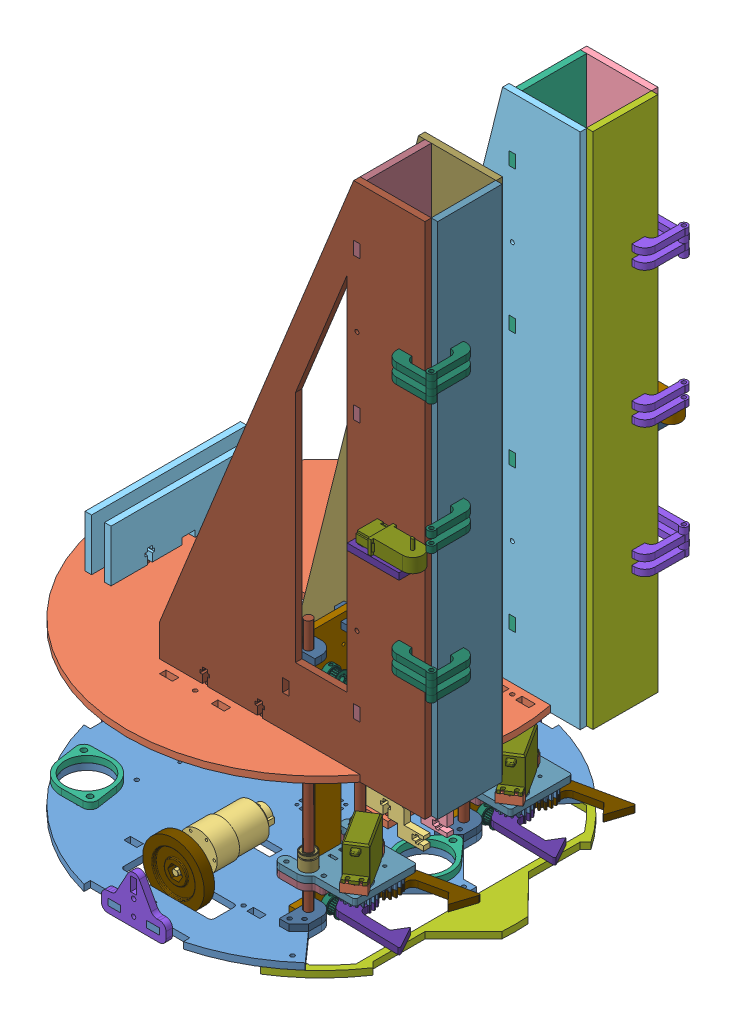
SolidWorks assembly Bot, configuration Default. Lengths in mm.
Overall size (426.1 677.49 381).
102 component instances, 45 part files, 65 mates.
Components (placement in the parent):
- Layer0-1: Layer0 [Default] at (287.9102 -30.6226 -253.9545) size (330.2 6.35 368.3)
- Layer1-1: Layer1 [Default] at (287.9102 128.1274 -253.9545) size (381 6.35 381)
- SideSupport-1: SideSupport [Default] at (364.1102 -24.2726 -133.3045) size (152.4 165.1 6.35) (hidden)
- SideSupport-2: SideSupport [Default] at (364.1102 -24.2726 -380.9545) size (152.4 165.1 6.35) (hidden)
- TailPlate-1: TailPlate [Default] at (138.6852 -30.6226 -291.5992) x (0 0 1) z (-1 0 0) size (76.2 165.1 6.35)
- BatteryHolder-1: BatteryHolder [Default] at (167.8952 -24.2726 -222.2045) x (0 0 -1) z (1 0 0) size (63.5 57.03 6.35)
- TabletHolder-1: TabletHolder [Default] at (138.6852 128.1274 -330.1545) x (0 0 1) z (-1 0 0) size (152.4 57.15 6.35)
- TabletHolder-2: TabletHolder [Default] at (157.7352 128.1274 -330.1545) x (0 0 1) z (-1 0 0) size (152.4 57.15 6.35)
- caster_spacer-1: caster_spacer [Default] at (152.6682 -24.2726 -348.652) x (0.584385 0 -0.811477) z (0 1 0) size (69.85 50.8 6.35)
- caster_spacer-2: caster_spacer [Default] at (152.6682 -17.9226 -159.257) x (0.760691 0 0.649114) z (0 -1 0) size (69.85 50.8 6.35)
- caster_spacer-3: caster_spacer [Default] at (389.5102 -17.9226 -253.9545) x (-0.01143 0 -0.999935) z (0 -1 0) size (69.85 50.8 6.35)
- CubeLimit-1: CubeLimit [Default] at (287.9102 -36.9726 -253.9545) size (88.9 6.35 322.29)
- ultra_short_ir_mount_plate-2: ultra_short_ir_mount_plate [Default] at (287.9102 -27.4476 -76.1545) size (63.5 47.06 6.35)
- ultra_short_ir_mount_plate-3: ultra_short_ir_mount_plate [Default] at (287.9102 -27.4476 -438.1045) size (63.5 47.06 6.35)
- ultra_short_ir_mount_plate-4: ultra_short_ir_mount_plate [Default] at (103.7602 -27.4476 -253.9545) x (0 0 -1) z (1 0 0) size (63.5 47.06 6.35)
- PulleyModule-1: PulleyModule [Default] at (324.3365 -56.1145 -530.8166) size (125.26 266.7 96.11)
  - PulleyBoard-1: PulleyBoard [Default] at (39.7737 6.4419 232.4121) size (6.35 247.65 63.5)
  - FrontBottom-1: FrontBottom [Default] at (39.7737 31.8419 340.3621) size (19.05 6.35 34.92)
  - FrontBottom-2: FrontBottom [Default] at (39.7737 38.1919 60.9621) x (1 0 0) z (0 0 -1) size (19.05 6.35 34.92)
  - Shaft8mm-1: Shaft8mm [Default] at (52.4737 31.8419 226.0621) size (8 254 8)
  - Shaft8mm-2: Shaft8mm [Default] at (52.4737 31.8419 175.2621) x (0.997108 0 -0.075996) z (0.075996 0 0.997108) size (8 254 8)
  - LM8UU-1: LM8UU [Default] at (52.4737 76.678 175.2621) x (0 -1 0) z (-0.618662 0 0.785658) size (24 15 15)
  - LM8UU-2: LM8UU [Default] at (52.4737 76.678 226.0621) x (0 -1 0) z (0 0 1) size (24 15 15)
  - 3DPrint-1: 3DPrint [Default] at (52.4737 61.503 200.6621) x (0 0 -1) z (1 0 0) size (73.42 6.35 41.67)
  - ClampSupport-1: ClampSupport [Default] at (52.4737 67.853 200.6621) x (0 0 -1) z (1 0 0) size (73.42 6.35 73.42)
  - GT2_20tooth-1: GT2_20tooth [Конфигурация1] at (46.1237 224.2919 200.6621) size (14 15 15)
  - GT2_20tooth-2: GT2_20tooth [Конфигурация1] at (46.1237 28.6669 200.6621) size (14 15 15)
  - power_hd_6001hb_servo-1: power_hd_6001hb_servo [Default] at (83.5903 112.303 204.4284) x (-0.538774 0 -0.84245) z (-0.84245 0 0.538774) size (54.5 43.74 20.07)
  - GearL-1: GearL [Default] at (89.3037 55.153 213.3621) x (0.999717 0 0.023781) z (-0.023781 0 0.999717) size (78.19 6.35 36.83)
  - GearR-1: GearR [Default] at (89.3037 55.153 187.9621) x (0.977961 0 -0.208788) z (0.208788 0 0.977961) size (78.31 6.35 36.71)
  - Gear-1: Gear [Default] at (89.3037 61.503 213.3621) x (0.947561 0 -0.319576) z (0.319576 0 0.947561) size (27.7 6.35 27.94)
  - Gear-2: Gear [Default] at (89.3037 61.503 187.9621) x (0.999359 0 -0.035795) z (0.035795 0 0.999359) size (27.7 6.35 27.94)
  - 3DPart2-1: 3DPart2 [Default] at (106.4689 74.203 221.7031) x (-0.538774 0 -0.84245) z (0.84245 0 -0.538774) size (54.5 8.56 20)
  - FrontBottom-3: FrontBottom [Default] at (-61.8263 254.0919 162.5621) x (0 0 1) z (-1 0 0) size (19.05 6.35 34.92)
  - FrontBottom-4: FrontBottom [Default] at (-61.8263 260.4419 238.7621) x (0 0 -1) z (-1 0 0) size (19.05 6.35 34.92)
- pololu_37d_29_motor_encoder-2: pololu_37d_29_motor_encoder [Default] at (287.914 -3.4296 -374.6045) x (0.000538 1 0) z (0 0 1) size (36.8 36.8 87.42)
- pololu_37d_29_motor_encoder-3: pololu_37d_29_motor_encoder [Default] at (287.9713 -3.4298 -133.3045) x (0.008727 0.999962 0) z (0 0 -1) size (36.8 36.8 87.42)
- ContainerUp-1: ContainerUp [Default] at (752.6603 -95.2272 -302.1038) x (0 0 1) z (-1 0 0) size (101.6 508 280.05)
  - ContainerTop-1: ContainerTop [Default] at (-66.1507 223.3546 509.2001) size (6.35 508 260.35)
  - ContainerBottom-1: ContainerBottom [Default] at (3.6993 223.3546 445.7001) x (0 0 -1) z (1 0 0) size (196.85 508 6.35)
  - ContainerLeft-1: ContainerLeft [Default] at (-66.1507 223.3546 312.3501) size (76.2 501.65 6.35)
  - ContainerRight-1: ContainerRight [Default] at (-59.8461 223.3546 242.5754) x (-0.004755 0 0.999989) z (-0.999989 0 -0.004755) size (6.35 508 63.5)
  - DoorJam-1: DoorJam [Default] at (-59.8007 591.6546 274.2501) x (0 0 -1) z (1 0 0) size (45.09 6.35 19.68)
  - DoorJam-2: DoorJam [Default] at (-59.8007 356.7046 274.2501) x (0 0 -1) z (1 0 0) size (45.09 6.35 19.68)
  - DoorJam-3: DoorJam [Default] at (-59.8007 604.3546 274.2501) x (0 0 -1) z (1 0 0) size (45.09 6.35 19.68)
  - DoorJam-4: DoorJam [Default] at (-59.8007 344.0046 274.2501) x (0 0 -1) z (1 0 0) size (45.09 6.35 19.68)
  - DoorJam-5: DoorJam [Default] at (-34.4765 617.0546 249.0461) x (-0.999989 0 -0.004755) z (-0.004755 0 0.999989) size (45.09 6.35 19.68)
  - DoorJam-6: DoorJam [Default] at (-34.4765 604.3546 249.0461) x (-0.999989 0 -0.004755) z (-0.004755 0 0.999989) size (45.09 6.35 19.68)
  - DoorJam-7: DoorJam [Default] at (-34.4765 471.0046 249.0461) x (-0.999989 0 -0.004755) z (-0.004755 0 0.999989) size (45.09 6.35 19.68)
  - DoorJam-8: DoorJam [Default] at (-34.4765 356.7046 249.0461) x (-0.999989 0 -0.004755) z (-0.004755 0 0.999989) size (45.09 6.35 19.68)
  - DoorJam-9: DoorJam [Default] at (-34.4765 344.0046 249.0461) x (-0.999989 0 -0.004755) z (-0.004755 0 0.999989) size (45.09 6.35 19.68)
  - DoorJam-10: DoorJam [Default] at (-34.4765 483.7046 249.0461) x (-0.999989 0 -0.004755) z (-0.004755 0 0.999989) size (45.09 6.35 19.68)
  - pololu_plastic_180_flat-1: pololu_plastic_180_flat [Default] at (-78.5507 452.5046 248.4602) x (0 0 1) z (0 1 0) size (54.5 24.8 23.5)
  - DoorServoHolder-1: DoorServoHolder [Default] at (-66.1507 445.6046 248.8501) x (0 0 1) z (1 0 0) size (50.8 6.35 31.75)
- MirrorContainerUp-4: MirrorContainerUp [Default] at (752.6603 -95.2272 -205.8052) x (0 0 -1) z (1 0 0) size (101.6 508 280.05)
  - MirrorContainerTop-1: MirrorContainerTop [Default] at (-66.1507 223.3546 -509.2001) size (6.35 508 260.35)
  - MirrorContainerBottom-1: MirrorContainerBottom [Default] at (3.6993 223.3546 -445.7001) x (0 0 1) z (-1 0 0) size (196.85 508 6.35)
  - MirrorContainerLeft-1: MirrorContainerLeft [Default] at (-66.1507 223.3546 -312.3501) size (76.2 501.65 6.35)
  - MirrorContainerRight-1: MirrorContainerRight [Default] at (-59.8461 223.3546 -242.5754) x (-0.004755 0 -0.999989) z (0.999989 0 -0.004755) size (6.35 508 63.5)
  - MirrorDoorJam-1: MirrorDoorJam [Default] at (-59.8007 591.6546 -274.2501) x (0 0 1) z (-1 0 0) size (45.09 6.35 19.68)
  - MirrorDoorJam-2: MirrorDoorJam [Default] at (-59.8007 356.7046 -274.2501) x (0 0 1) z (-1 0 0) size (45.09 6.35 19.68)
  - MirrorDoorJam-3: MirrorDoorJam [Default] at (-59.8007 604.3546 -274.2501) x (0 0 1) z (-1 0 0) size (45.09 6.35 19.68)
  - MirrorDoorJam-4: MirrorDoorJam [Default] at (-59.8007 344.0046 -274.2501) x (0 0 1) z (-1 0 0) size (45.09 6.35 19.68)
  - MirrorDoorJam-5: MirrorDoorJam [Default] at (-34.4765 617.0546 -249.0461) x (-0.999989 0 0.004755) z (0.004755 0 0.999989) size (45.09 6.35 19.68)
  - MirrorDoorJam-6: MirrorDoorJam [Default] at (-34.4765 604.3546 -249.0461) x (-0.999989 0 0.004755) z (0.004755 0 0.999989) size (45.09 6.35 19.68)
  - MirrorDoorJam-7: MirrorDoorJam [Default] at (-34.4765 471.0046 -249.0461) x (-0.999989 0 0.004755) z (0.004755 0 0.999989) size (45.09 6.35 19.68)
  - MirrorDoorJam-8: MirrorDoorJam [Default] at (-34.4765 356.7046 -249.0461) x (-0.999989 0 0.004755) z (0.004755 0 0.999989) size (45.09 6.35 19.68)
  - MirrorDoorJam-9: MirrorDoorJam [Default] at (-34.4765 344.0046 -249.0461) x (-0.999989 0 0.004755) z (0.004755 0 0.999989) size (45.09 6.35 19.68)
  - MirrorDoorJam-10: MirrorDoorJam [Default] at (-34.4765 483.7046 -249.0461) x (-0.999989 0 0.004755) z (0.004755 0 0.999989) size (45.09 6.35 19.68)
  - Mirrorpololu_plastic_180_flat-1: Mirrorpololu_plastic_180_flat [Default] at (-78.5507 452.5046 -248.4602) x (0 0 -1) z (0 -1 0) size (54.5 24.8 23.5)
  - MirrorDoorServoHolder-1: MirrorDoorServoHolder [Default] at (-66.1507 445.6046 -248.8501) x (0 0 -1) z (-1 0 0) size (50.8 6.35 31.75)
- PulleyModule-7: PulleyModule [Default] at (324.3365 -56.1145 -378.4166) size (125.26 266.7 96.11)
  - PulleyBoard-1: PulleyBoard [Default] at (39.7737 6.4419 232.4121) size (6.35 247.65 63.5)
  - FrontBottom-1: FrontBottom [Default] at (39.7737 31.8419 340.3621) size (19.05 6.35 34.92)
  - FrontBottom-2: FrontBottom [Default] at (39.7737 38.1919 60.9621) x (1 0 0) z (0 0 -1) size (19.05 6.35 34.92)
  - Shaft8mm-1: Shaft8mm [Default] at (52.4737 31.8419 226.0621) size (8 254 8)
  - Shaft8mm-2: Shaft8mm [Default] at (52.4737 31.8419 175.2621) x (0.997108 0 -0.075996) z (0.075996 0 0.997108) size (8 254 8)
  - LM8UU-1: LM8UU [Default] at (52.4737 76.678 175.2621) x (0 -1 0) z (-0.618662 0 0.785658) size (24 15 15)
  - LM8UU-2: LM8UU [Default] at (52.4737 76.678 226.0621) x (0 -1 0) z (0 0 1) size (24 15 15)
  - 3DPrint-1: 3DPrint [Default] at (52.4737 61.503 200.6621) x (0 0 -1) z (1 0 0) size (73.42 6.35 41.67)
  - ClampSupport-1: ClampSupport [Default] at (52.4737 67.853 200.6621) x (0 0 -1) z (1 0 0) size (73.42 6.35 73.42)
  - GT2_20tooth-1: GT2_20tooth [Конфигурация1] at (46.1237 224.2919 200.6621) size (14 15 15)
  - GT2_20tooth-2: GT2_20tooth [Конфигурация1] at (46.1237 28.6669 200.6621) size (14 15 15)
  - power_hd_6001hb_servo-1: power_hd_6001hb_servo [Default] at (83.5903 112.303 204.4284) x (-0.538774 0 -0.84245) z (-0.84245 0 0.538774) size (54.5 43.74 20.07)
  - GearL-1: GearL [Default] at (89.3037 55.153 213.3621) x (0.999717 0 0.023781) z (-0.023781 0 0.999717) size (78.19 6.35 36.83)
  - GearR-1: GearR [Default] at (89.3037 55.153 187.9621) x (0.977961 0 -0.208788) z (0.208788 0 0.977961) size (78.31 6.35 36.71)
  - Gear-1: Gear [Default] at (89.3037 61.503 213.3621) x (0.947561 0 -0.319576) z (0.319576 0 0.947561) size (27.7 6.35 27.94)
  - Gear-2: Gear [Default] at (89.3037 61.503 187.9621) x (0.999359 0 -0.035795) z (0.035795 0 0.999359) size (27.7 6.35 27.94)
  - 3DPart2-1: 3DPart2 [Default] at (106.4689 74.203 221.7031) x (-0.538774 0 -0.84245) z (0.84245 0 -0.538774) size (54.5 8.56 20)
  - FrontBottom-3: FrontBottom [Default] at (-61.8263 254.0919 162.5621) x (0 0 1) z (-1 0 0) size (19.05 6.35 34.92)
  - FrontBottom-4: FrontBottom [Default] at (-61.8263 260.4419 238.7621) x (0 0 -1) z (-1 0 0) size (19.05 6.35 34.92)
- banebots_wheel_2_3_8-1: banebots_wheel_2_3_8 [Default] at (287.9102 -10.4296 -393.972) x (0.999663 0.025959 0) z (0 0 1) size (60.32 60.32 10.16)
- banebots_wheel_2_3_8-2: banebots_wheel_2_3_8 [Default] at (287.9102 -10.4296 -113.937) size (60.32 60.32 10.16)
- Camera-1: Camera [Default] at (348.6134 148.8265 -115.4512) x (1 0 0) z (0 -1 0) size (175.21 63.5 128.59)
  - MirrorCameraSide-3: MirrorCameraSide [Default] at (-10.4832 -121.8345 58.7991) x (1 0 0) z (0 0 -1) size (31.75 35.72 6.35)
  - CameraSide-3: CameraSide [Default] at (-10.4832 -121.8345 144.5241) x (1 0 0) z (0 0 -1) size (31.75 35.72 6.35)
  - CameraBottom-2: CameraBottom [Default] at (-10.4832 -131.3595 119.1241) size (63.5 6.35 95.25)
  - CameraTopHack-3: CameraTopHack [Default] at (-10.4832 -148.0283 84.1991) x (1 0 0) z (0 0 -1) size (63.5 6.35 95.25)
  - CameraHang-1: CameraHang [Default] at (27.6168 -138.5033 65.1491) x (0 -1 0) z (1 0 0) size (6.35 85.72 88.9)
  - FrontIRHack-2: FrontIRHack [Default] at (53.0168 -119.4533 106.4241) x (0 -1 0) z (1 0 0) size (50.8 6.35 133.35)
  - FrontIR-1: FrontIR [Default] at (62.5418 -144.8533 87.3741) x (0 1 0) z (-1 0 0) size (25.4 50.8 6.35)
  - CameraTopTop-2: CameraTopTop [Default] at (110.7468 -106.7533 27.0491) x (0 -1 0) z (1 0 0) size (63.5 6.35 127)
Mates (geometry in assembly coordinates):
- Coincident13: coincident anti-aligned: plane of Layer0-1 through (287.9102 -24.2726 -253.9545) normal (0 1 0); plane of SideSupport-1 through (333.154 -24.2726 -126.9545) normal (0 -1 0)
- Coincident14: coincident anti-aligned: plane of Layer0-1 through (341.8852 -30.6226 -253.9545) normal (1 0 0); plane of SideSupport-1 through (341.8852 -24.2726 -126.9545) normal (-1 0 0)
- Coincident15: coincident anti-aligned: plane of Layer0-1 through (287.9102 -30.6226 -133.3045) normal (0 0 1); plane of SideSupport-1 through (364.1102 -24.2726 -133.3045) normal (0 0 -1)
- Coincident16: coincident anti-aligned: plane of Layer1-1 through (287.9102 128.1274 -253.9545) normal (0 -1 0); plane of SideSupport-1 through (268.8602 128.1274 -126.9545) normal (0 1 0)
- Coincident17: coincident anti-aligned: plane of Layer1-1 through (268.8602 128.1274 -133.3045) normal (-1 0 0); plane of SideSupport-1 through (268.8602 128.1274 -126.9545) normal (1 0 0)
- Coincident18: coincident anti-aligned: plane of Layer1-1 through (268.8602 128.1274 -133.3045) normal (0 0 1); plane of SideSupport-1 through (364.1102 -24.2726 -133.3045) normal (0 0 -1)
- Coincident19: coincident anti-aligned: plane of Layer0-1 through (221.2352 -30.6226 -253.9545) normal (1 0 0); plane of SideSupport-2 through (221.2352 -24.2726 -374.6045) normal (-1 0 0)
- Coincident20: coincident anti-aligned: plane of Layer0-1 through (287.9102 -24.2726 -253.9545) normal (0 1 0); plane of SideSupport-2 through (333.154 -24.2726 -374.6045) normal (0 -1 0)
- Coincident21: coincident anti-aligned: plane of Layer0-1 through (287.9102 -30.6226 -380.9545) normal (0 0 1); plane of SideSupport-2 through (364.1102 -24.2726 -380.9545) normal (0 0 -1)
- Coincident53: coincident anti-aligned: plane of Layer0-1 through (138.6852 -30.6226 -228.5545) normal (-1 0 0); plane of TailPlate-1 through (138.6852 -30.6226 -291.5992) normal (1 0 0)
- Coincident54: coincident anti-aligned: plane of Layer1-1 through (132.3352 128.1274 -228.5545) normal (0 0 -1); plane of TailPlate-1 through (132.3352 -30.6226 -228.5545) normal (0 0 1)
- Coincident55: coincident anti-aligned: plane of Layer0-1 through (287.9102 -24.2726 -253.9545) normal (0 1 0); plane of TailPlate-1 through (132.3352 -24.2726 -291.5992) normal (0 -1 0)
- Coincident59: coincident anti-aligned: plane of Layer0-1 through (174.2452 -30.6226 -241.2545) normal (-1 0 0); plane of BatteryHolder-1 through (174.2452 -24.2726 -222.2045) normal (1 0 0)
- Coincident60: coincident anti-aligned: plane of Layer0-1 through (287.9102 -24.2726 -253.9545) normal (0 1 0); plane of BatteryHolder-1 through (174.2452 -24.2726 -222.2045) normal (0 -1 0)
- Coincident61: coincident anti-aligned: plane of Layer0-1 through (174.2452 -30.6226 -228.5545) normal (0 0 -1); plane of BatteryHolder-1 through (174.2452 -24.2726 -228.5545) normal (0 0 1)
- Coincident64: coincident anti-aligned: plane of Layer1-1 through (138.6852 128.1274 -190.4545) normal (-1 0 0); plane of TabletHolder-1 through (138.6852 128.1274 -330.1545) normal (1 0 0)
- Coincident65: coincident anti-aligned: plane of Layer1-1 through (132.3352 128.1274 -203.1545) normal (0 0 1); plane of TabletHolder-1 through (132.3352 128.1274 -203.1545) normal (0 0 -1)
- Coincident66: coincident anti-aligned: plane of Layer1-1 through (287.9102 134.4774 -253.9545) normal (0 1 0); plane of TabletHolder-1 through (132.3352 134.4774 -304.7545) normal (0 -1 0)
- Coincident67: coincident anti-aligned: plane of Layer1-1 through (157.7352 128.1274 -203.1545) normal (-1 0 0); plane of TabletHolder-2 through (157.7352 128.1274 -330.1545) normal (1 0 0)
- Coincident68: coincident anti-aligned: plane of Layer1-1 through (151.3852 128.1274 -203.1545) normal (0 0 1); plane of TabletHolder-2 through (151.3852 128.1274 -203.1545) normal (0 0 -1)
- Coincident69: coincident anti-aligned: plane of Layer1-1 through (287.9102 134.4774 -253.9545) normal (0 1 0); plane of TabletHolder-2 through (151.3852 134.4774 -330.1545) normal (0 -1 0)
- Coincident70: coincident anti-aligned: plane of Layer0-1 through (287.9102 -24.2726 -253.9545) normal (0 1 0); plane of caster_spacer-1 through (152.6682 -24.2726 -348.652) normal (0 -1 0)
- Concentric2: concentric aligned: circle of Layer0-1; circle of caster_spacer-1
- Coincident74: coincident anti-aligned: plane of Layer0-1 through (287.9102 -24.2726 -253.9545) normal (0 1 0); plane of caster_spacer-2 through (152.6682 -24.2726 -159.257) normal (0 -1 0)
- Concentric5: concentric aligned: circle of Layer0-1; circle of caster_spacer-2
- Concentric12: concentric aligned: circle of Layer0-1; circle of CubeLimit-1
- Coincident101: coincident anti-aligned: plane of Layer0-1 through (287.9102 -30.6226 -253.9545) normal (0 -1 0); plane of CubeLimit-1 through (287.9102 -30.6226 -253.9545) normal (0 1 0)
- Coincident103: coincident aligned: circle of Layer0-1; circle of CubeLimit-1
- Coincident114: coincident anti-aligned: plane of Layer0-1 through (287.9102 -24.2726 -253.9545) normal (0 1 0); plane of caster_spacer-3 through (389.5102 -24.2726 -253.9545) normal (0 -1 0)
- Concentric18: concentric anti-aligned: circle of Layer0-1; circle of caster_spacer-3
- Coincident125: coincident anti-aligned: plane of Layer0-1 through (281.5602 -24.2726 -76.1545) normal (0 0 1); plane of ultra_short_ir_mount_plate-2 through (287.9102 -27.4476 -76.1545) normal (0 0 -1)
- Coincident126: coincident anti-aligned: plane of Layer0-1 through (287.9102 -30.6226 -253.9545) normal (0 -1 0); plane of ultra_short_ir_mount_plate-2 through (300.6102 -30.6226 -76.1545) normal (0 1 0)
- Coincident127: coincident anti-aligned: plane of Layer0-1 through (300.6102 -24.2726 -69.8045) normal (-1 0 0); plane of ultra_short_ir_mount_plate-2 through (300.6102 -24.2726 -76.1545) normal (1 0 0)
- Coincident128: coincident anti-aligned: plane of Layer0-1 through (336.6855 -24.2726 -431.7545) normal (0 0 -1); plane of ultra_short_ir_mount_plate-3 through (287.9102 -27.4476 -431.7545) normal (0 0 1)
- Coincident129: coincident anti-aligned: plane of Layer0-1 through (287.9102 -30.6226 -253.9545) normal (0 -1 0); plane of ultra_short_ir_mount_plate-3 through (262.5102 -30.6226 -438.1045) normal (0 1 0)
- Coincident130: coincident anti-aligned: plane of Layer0-1 through (262.5102 -24.2726 -431.7545) normal (-1 0 0); plane of ultra_short_ir_mount_plate-3 through (262.5102 -24.2726 -438.1045) normal (1 0 0)
- Coincident131: coincident anti-aligned: plane of Layer0-1 through (110.1102 -24.2726 -253.9545) normal (-1 0 0); plane of ultra_short_ir_mount_plate-4 through (110.1102 -27.4476 -253.9545) normal (1 0 0)
- Coincident132: coincident anti-aligned: plane of Layer0-1 through (110.1102 -24.2726 -241.2545) normal (0 0 -1); plane of ultra_short_ir_mount_plate-4 through (103.7602 -24.2726 -241.2545) normal (0 0 1)
- Coincident133: coincident anti-aligned: plane of Layer0-1 through (287.9102 -30.6226 -253.9545) normal (0 -1 0); plane of ultra_short_ir_mount_plate-4 through (103.7602 -30.6226 -228.5545) normal (0 1 0)
- Coincident138: coincident anti-aligned: plane of Layer0-1 through (287.9102 -30.6226 -253.9545) normal (0 -1 0); plane of PulleyModule-1/PulleyBoard-1 through (370.4602 -30.6226 -298.4045) normal (0 1 0)
- Coincident140: coincident anti-aligned: plane of Layer1-1 through (287.9102 128.1274 -342.8545) normal (0 0 1); plane of PulleyModule-1/PulleyBoard-1 through (370.4602 134.4774 -342.8545) normal (0 0 -1)
- Coincident142: coincident anti-aligned: plane of Layer1-1 through (364.1102 128.1274 -253.9545) normal (1 0 0); plane of PulleyModule-1/PulleyBoard-1 through (364.1102 -49.6726 -298.4045) normal (-1 0 0)
- Coincident147: coincident anti-aligned: plane of SideSupport-2 through (364.1102 -24.2726 -374.6045) normal (0 0 1); plane of pololu_37d_29_motor_encoder-2 through (287.914 -3.4296 -374.6045) normal (0 0 -1)
- Concentric35: concentric aligned: circle of SideSupport-2; circle of pololu_37d_29_motor_encoder-2
- Coincident148: coincident anti-aligned: plane of SideSupport-1 through (364.1102 -24.2726 -133.3045) normal (0 0 -1); plane of pololu_37d_29_motor_encoder-3 through (287.9713 -3.4298 -133.3045) normal (0 0 1)
- Concentric39: concentric anti-aligned: circle of SideSupport-1; circle of pololu_37d_29_motor_encoder-3
- Coincident149: coincident anti-aligned: plane of Layer1-1 through (287.9102 128.1274 -215.8545) normal (0 0 1); plane of MirrorContainerUp-4/MirrorContainerBottom-1 through (306.9602 128.1274 -215.8545) normal (0 0 -1)
- Coincident150: coincident anti-aligned: plane of Layer1-1 through (287.9102 134.4774 -253.9545) normal (0 1 0); plane of MirrorContainerUp-4/MirrorContainerTop-1 through (243.4602 134.4774 -146.0045) normal (0 -1 0)
- Coincident151: coincident anti-aligned: plane of Layer1-1 through (440.3102 128.1274 -253.9545) normal (1 0 0); plane of MirrorContainerUp-4/MirrorContainerTop-1 through (440.3102 128.1274 -146.0045) normal (-1 0 0)
- Coincident153: coincident anti-aligned: plane of Layer1-1 through (287.9102 134.4774 -253.9545) normal (0 1 0); plane of ContainerUp-1/ContainerBottom-1 through (465.7102 134.4774 -292.0545) normal (0 -1 0)
- Coincident154: coincident anti-aligned: plane of Layer1-1 through (326.0102 128.1274 -292.0545) normal (0 0 -1); plane of ContainerUp-1/ContainerBottom-1 through (306.9602 128.1274 -292.0545) normal (0 0 1)
- Coincident156: coincident anti-aligned: plane of Layer1-1 through (440.3102 128.1274 -253.9545) normal (1 0 0); plane of ContainerUp-1/ContainerTop-1 through (440.3102 128.1274 -361.9045) normal (-1 0 0)
- Coincident157: coincident anti-aligned: plane of Layer0-1 through (364.1102 -24.2726 -171.4045) normal (1 0 0); plane of PulleyModule-7/PulleyBoard-1 through (364.1102 -49.6726 -146.0045) normal (-1 0 0)
- Coincident158: coincident anti-aligned: plane of Layer0-1 through (287.9102 -24.2726 -253.9545) normal (0 1 0); plane of PulleyModule-7/FrontBottom-1 through (364.1102 -24.2726 -38.0545) normal (0 -1 0)
- Coincident159: coincident anti-aligned: plane of Layer0-1 through (370.4602 -24.2726 -184.1045) normal (0 0 1); plane of PulleyModule-7/PulleyBoard-1 through (364.1102 -24.2726 -184.1045) normal (0 0 -1)
- Coincident163: coincident aligned: circle of pololu_37d_29_motor_encoder-2; plane of banebots_wheel_2_3_8-1 through (287.9102 -10.4296 -397.4645) normal (0 0 -1)
- Concentric43: concentric aligned: circle of pololu_37d_29_motor_encoder-2; circle of banebots_wheel_2_3_8-1
- Coincident164: coincident aligned: plane of pololu_37d_29_motor_encoder-3 through (287.9713 -3.4298 -110.4445) normal (0 0 1); plane of banebots_wheel_2_3_8-2 through (287.9102 -10.4296 -110.4445) normal (0 0 1)
- Concentric44: concentric aligned: circle of pololu_37d_29_motor_encoder-3; circle of banebots_wheel_2_3_8-2
- Coincident165: coincident anti-aligned: plane of Layer1-1 through (287.9102 128.1274 -253.9545) normal (0 -1 0); plane of Camera-1/CameraTopTop-2 through (459.3602 128.1274 -222.2045) normal (0 1 0)
- Concentric45: concentric aligned: circle of Layer1-1; circle of Camera-1/CameraTopTop-2
- Concentric46: concentric aligned: circle of Layer1-1; circle of Camera-1/CameraTopTop-2
- Coincident166: coincident anti-aligned: plane of Layer1-1 through (287.9102 128.1274 -253.9545) normal (0 -1 0); plane of Camera-1/CameraTopTop-2 through (459.3602 128.1274 -222.2045) normal (0 1 0)
- Concentric47: concentric aligned: circle of Layer1-1; circle of Camera-1/CameraTopTop-2
- Concentric48: concentric aligned: circle of Layer1-1; circle of Camera-1/CameraTopTop-2
